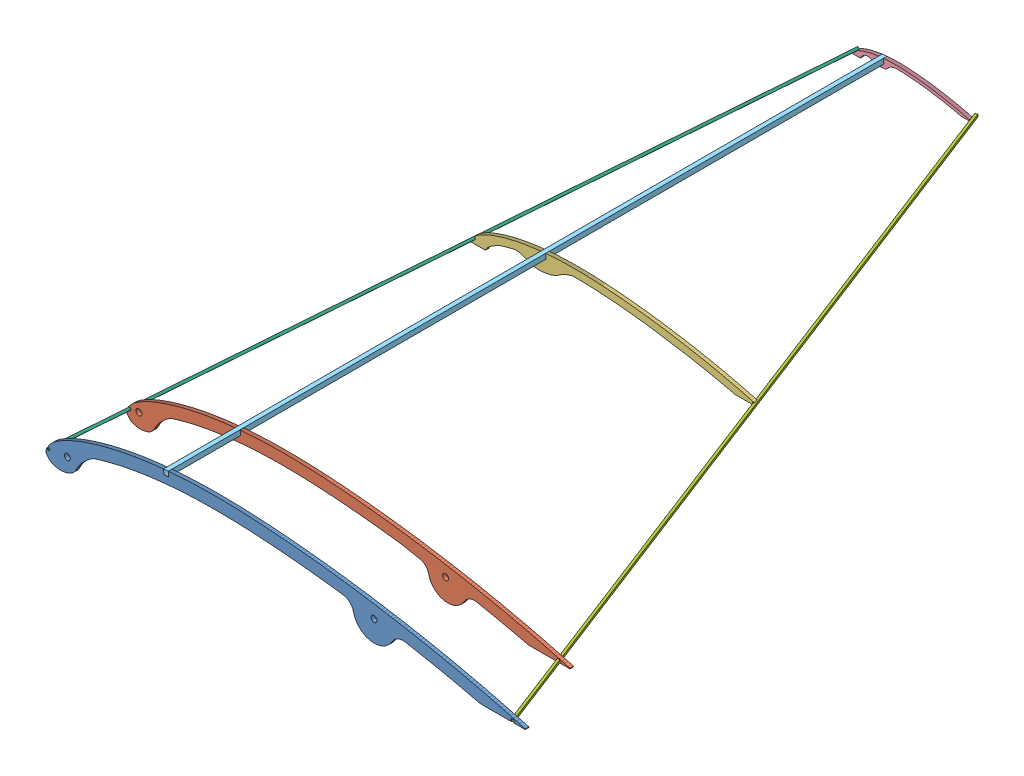
SolidWorks assembly unit05_mainwingR, configuration ﾃﾞﾌｫﾙﾄ. Lengths in mm.
Overall size (400.11 45.91 603.5).
7 component instances, 7 part files, 18 mates.
Components (placement in the parent):
- unit05_mainwing1-1: unit05_mainwing1 [ﾃﾞﾌｫﾙﾄ] at (-466.6327 -212.5638 398.6066) size (400.11 45.91 3)
- unit05_mainwing2-1: unit05_mainwing2 [ﾃﾞﾌｫﾙﾄ] at (-470.5081 -179.0541 338.6066) size (370.1 42.47 3)
- unit05_mainwing3-1: unit05_mainwing3 [ﾃﾞﾌｫﾙﾄ] at (-468.3496 -152.7229 83.6066) size (236.35 23.96 3)
- unit05_mainwing4-1: unit05_mainwing4 [ﾃﾞﾌｫﾙﾄ] at (-504.22 -135.1556 -198.3934) size (97.1 9.88 3)
- unit05_mainspar-1: unit05_mainspar [ﾃﾞﾌｫﾙﾄ] at (-360.8252 -120.8753 -198.3934) x (0.996195 0.087156 0) z (0 0 1) size (4 4 600)
- unit05_leadingedge-1: unit05_leadingedge [ﾃﾞﾌｫﾙﾄ] at (-382.5656 -124.3838 -197.7317) x (0.698309 0.705287 0.122209) z (-0.1264 -0.046548 0.990887) size (2 2 604.67)
- unit05_trailingedge-1: unit05_trailingedge [ﾃﾞﾌｫﾙﾄ] at (-287.4821 -127.0266 -201.5162) x (0.941371 -0.008799 -0.337258) z (0.336574 -0.044257 0.940616) size (2 2 640.8)
Mates (geometry in assembly coordinates):
- 一致1: coincident anti-aligned: plane of unit05_mainwing1-1 through (-473.6154 -132.7508 401.6066) normal (-0.087156 0.996195 0); plane of unit05_mainspar-1 through (-362.6433 -123.042 401.6066) normal (0.087156 -0.996195 0)
- 一致2: coincident anti-aligned: plane of unit05_mainwing1-1 through (-355.6606 -202.855 401.6066) normal (0.996195 0.087156 0); plane of unit05_mainspar-1 through (-362.9919 -119.0572 401.6066) normal (-0.996195 -0.087156 0)
- 一致4: coincident anti-aligned: plane of unit05_mainwing2-1 through (-474.552 -132.8327 341.6066) normal (-0.087156 0.996195 0); plane of unit05_mainspar-1 through (-362.6433 -123.042 401.6066) normal (0.087156 -0.996195 0)
- 一致5: coincident anti-aligned: plane of unit05_mainwing2-1 through (-358.5995 -169.2634 341.6066) normal (0.996195 0.087156 0); plane of unit05_mainspar-1 through (-362.9919 -119.0572 401.6066) normal (-0.996195 -0.087156 0)
- 一致8: coincident anti-aligned: plane of unit05_mainwing4-1 through (-504.1963 -135.4263 -195.3934) normal (-0.087156 0.996195 0); plane of unit05_mainspar-1 through (-362.6433 -123.042 401.6066) normal (0.087156 -0.996195 0)
- 一致9: coincident anti-aligned: plane of unit05_mainwing4-1 through (-358.6822 -122.4227 -195.3934) normal (-0.996195 -0.087156 0); plane of unit05_mainspar-1 through (-359.0072 -118.7086 401.6066) normal (0.996195 0.087156 0)
- 一致10: coincident anti-aligned: plane of unit05_mainwing3-1 through (-356.8845 -142.971 86.6066) normal (-0.996195 -0.087156 0); plane of unit05_mainspar-1 through (-359.0072 -118.7086 401.6066) normal (0.996195 0.087156 0)
- 一致12: coincident: line of unit05_mainwing3-1 through (-358.6585 -122.6933 86.6066) axis (0 0 -1); plane of unit05_mainspar-1 through (-362.6433 -123.042 401.6066) normal (0.087156 -0.996195 0)
- 一致13: coincident aligned: plane of unit05_mainwing1-1 through (-466.6327 -212.5638 401.6066) normal (0 0 1); plane of unit05_mainspar-1 through (-360.8252 -120.8753 401.6066) normal (0 0 1)
- 一致14: coincident aligned: plane of unit05_mainwing4-1 through (-504.22 -135.1556 -198.3934) normal (0 0 -1); plane of unit05_mainspar-1 through (-360.8252 -120.8753 -198.3934) normal (0 0 -1)
- 距離1: distance = 60 mm aligned: plane of unit05_mainwing1-1 through (-466.6327 -212.5638 401.6066) normal (0 0 1); plane of unit05_mainwing2-1 through (-470.5081 -179.0541 341.6066) normal (0 0 1)
- 距離2: distance = 255 mm aligned: plane of unit05_mainwing2-1 through (-470.5081 -179.0541 341.6066) normal (0 0 1); plane of unit05_mainwing3-1 through (-468.3496 -152.7229 86.6066) normal (0 0 1)
- 一致16: coincident: line of unit05_mainwing1-1 through (-457.5929 -152.5321 401.6066) axis (-0.707107 -0.707107 0); point of unit05_leadingedge-1
- 一致17: coincident: line of unit05_mainwing1-1 through (-457.5929 -152.5321 401.6066) axis (-0.707107 0.707107 0); point of unit05_leadingedge-1
- 一致18: coincident: line of unit05_mainwing4-1 through (-382.5594 -125.7965 -195.3934) axis (0 0 -1); point of unit05_leadingedge-1
- 一致19: coincident: line of unit05_mainwing1-1 through (-72.7234 -156.5229 401.6066) axis (0 1 0); point of unit05_trailingedge-1
- 一致20: coincident: line of unit05_mainwing1-1 through (-72.7234 -154.3787 401.6066) axis (1 0 0); point of unit05_trailingedge-1
- 一致21: coincident: point of unit05_mainwing4-1; plane of unit05_trailingedge-1 through (-72.7234 -154.3787 401.6066) normal (-0.941371 0.008799 0.337258)
